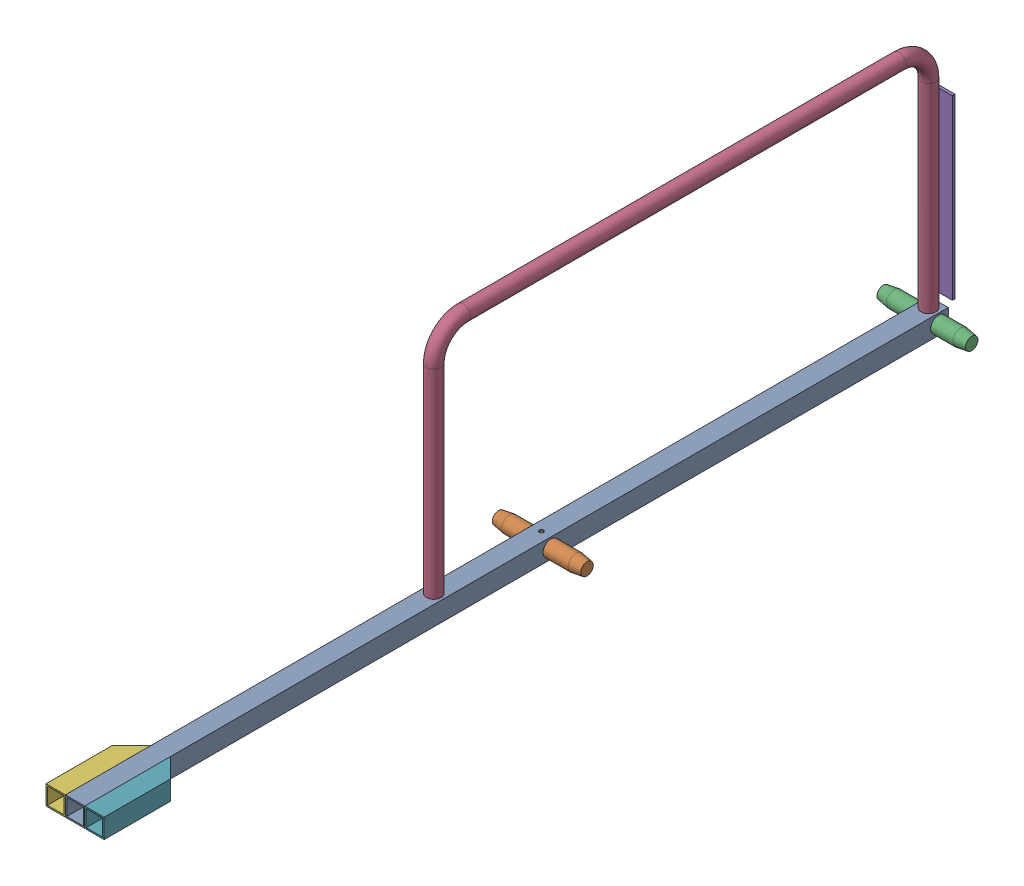
SolidWorks assembly FE-00001_, configuration Default. Lengths in mm.
Overall size (209.55 585.85 1981.2).
7 component instances, 5 part files, 0 mates.
Components (placement in the parent):
- FE-00001-05_-1: FE-00001-05_ [Default] at origin size (44.45 44.45 1981.2)
- FE-00001-04_-1: FE-00001-04_ [Default] at (-107.5178 -12.3404 906.3863) x (0 0 -1) z (1 0 0) size (36.51 36.51 203.2)
- FE-00001-04_-2: FE-00001-04_ [Default] at (-113.8678 -12.3404 17.3863) x (0 0 -1) z (1 0 0) size (36.51 36.51 203.2)
- FE-00001-03_-1: FE-00001-03_ [Default] at (-9.0928 595.693 1010.0407) x (0 1 0) z (-1 0 0) size (541.4 1168.46 33.4)
- FE-00001-02_-1: FE-00001-02_ [Default] at (-27.7615 418.9726 6.35) x (0 -1 0) z (0 0 -1) size (406.4 76.2 6.35)
- FE-00001-01_-1: FE-00001-01_ [Default] at (-49.0499 8.6298 1784.35) x (0 1 0) z (0 0 1) size (44.45 44.45 196.85)
- FE-00001-01_-2: FE-00001-01_ [Default] at (30.8643 -8.1185 1784.35) x (0 -1 0) z (0 0 1) size (44.45 44.45 196.85)
